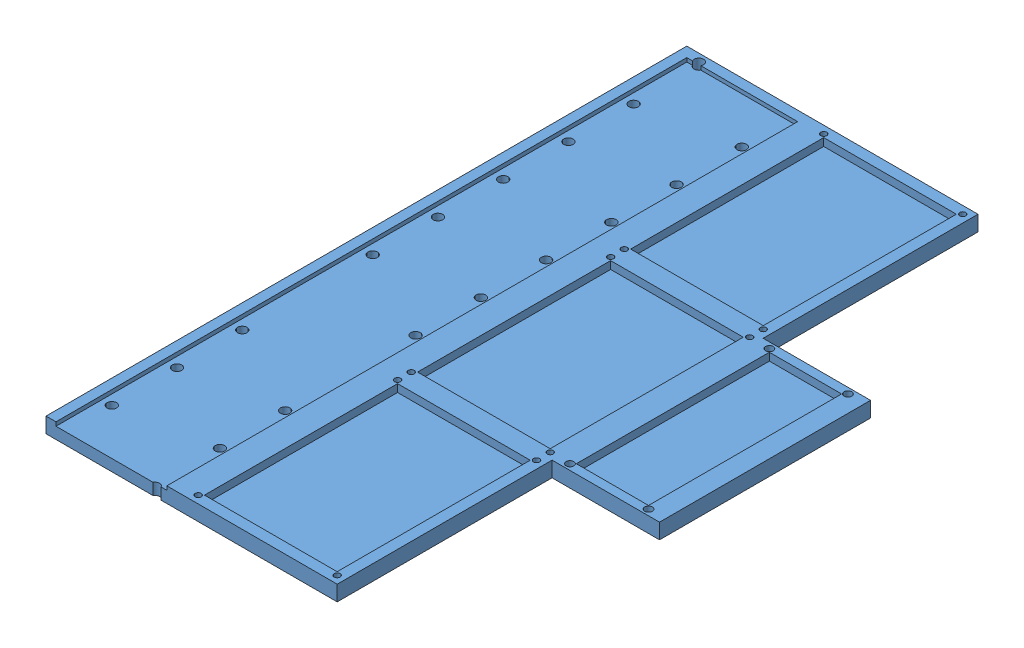
SolidWorks assembly Driver_power_housing_v1, configuration Default. Lengths in mm.
Overall size (131.94 5.08 212.09).
15 component instances, 4 part files, 17 mates.
Components (placement in the parent):
- pcb3x7-1: pcb3x7 [Default] at (-73.0022 6.604 -102.1286) x (0 0 -1) z (-1 0 0) size (70 1.52 30) (hidden)
- Carte proto 7x5.stp-1: Carte proto 7x5.stp [Default] at (-114.2326 6.58 -178.1987) x (0 0 1) z (0 -1 0) size (70 50 1.55) (hidden)
- DC-DC XL6009E1-2: DC-DC XL6009E1 [По умолчанию] at (-163.4226 5.08 -203.1712) size (43.3 13.75 21.1) (hidden)
- DC-DC XL6009E1-3: DC-DC XL6009E1 [По умолчанию] at (-163.4226 5.08 -181.5812) size (43.3 13.75 21.1) (hidden)
- DC-DC XL6009E1-4: DC-DC XL6009E1 [По умолчанию] at (-163.4226 5.08 -159.9912) size (43.3 13.75 21.1) (hidden)
- DC-DC XL6009E1-5: DC-DC XL6009E1 [По умолчанию] at (-163.4226 5.08 -138.4012) size (43.3 13.75 21.1) (hidden)
- DC-DC XL6009E1-6: DC-DC XL6009E1 [По умолчанию] at (-163.4226 5.08 -116.8112) size (43.3 13.75 21.1) (hidden)
- DC-DC XL6009E1-7: DC-DC XL6009E1 [По умолчанию] at (-163.4226 5.08 -95.2212) size (43.3 13.75 21.1) (hidden)
- DC-DC XL6009E1-8: DC-DC XL6009E1 [По умолчанию] at (-163.4226 5.08 -73.6312) size (43.3 13.75 21.1) (hidden)
- DC-DC XL6009E1-9: DC-DC XL6009E1 [По умолчанию] at (-163.4226 5.08 -52.0412) size (43.3 13.75 21.1) (hidden)
- DC-DC XL6009E1-10: DC-DC XL6009E1 [По умолчанию] at (-163.4226 5.08 -30.4512) size (43.3 13.75 21.1) (hidden)
- DC-DC XL6009E1-11: DC-DC XL6009E1 [По умолчанию] at (-163.4226 5.08 -8.8612) size (43.3 13.75 21.1) (hidden)
- Part4^Driver_power_housing_v1-1: Part4^Driver_power_housing_v1 [Default] at origin size (131.94 5.08 212.09) (virtual)
- Carte proto 7x5.stp-2: Carte proto 7x5.stp [Default] at (-114.2326 6.58 -37.1537) x (0 0 -1) z (0 -1 0) size (70 50 1.55) (hidden)
- Carte proto 7x5.stp-3: Carte proto 7x5.stp [Default] at (-114.2326 6.58 -107.6762) x (0 0 -1) z (0 -1 0) size (70 50 1.55) (hidden)
Mates (geometry in assembly coordinates):
- Coincident11: coincident: plane of DC-DC XL6009E1-2 through (-185.0726 6.68 -192.6212) normal (-1 0 0); plane of Part4^Driver_power_housing_v1-1 through (-185.0726 5.08 -1.6312) normal (-1 0 0)
- Coincident12: coincident: plane of DC-DC XL6009E1-2 through (-163.4226 5.08 -203.1712) normal (0 -1 0); plane of Part4^Driver_power_housing_v1-1 through (0 5.08 0) normal (0 1 0)
- Coincident30: coincident: plane of DC-DC XL6009E1-2 through (-185.0726 6.68 -213.7212) normal (0 0 -1); plane of Part4^Driver_power_housing_v1-1 through (-88.6883 5.08 -213.7212) normal (0 0 -1)
- Coincident14: coincident: plane of pcb3x7-1 through (-73.0022 5.08 -102.1286) normal (0 -1 0); plane of Part4^Driver_power_housing_v1-1 through (0 5.08 0) normal (0 1 0)
- Parallel2: parallel: plane of pcb3x7-1 through (-86.6926 5.08 -72.6762) normal (-1 0 0); plane of DC-DC XL6009E1-2 through (-141.7726 6.68 -192.6212) normal (1 0 0)
- Distance3: distance = 2.54 mm: plane of pcb3x7-1 through (-86.6926 5.08 -72.6762) normal (-1 0 0); plane of Carte proto 7x5.stp-3 through (-89.2326 6.58 -72.6762) normal (1 0 0)
- Coincident17: coincident: plane of Carte proto 7x5.stp-1 through (-114.2326 5.08 -178.1987) normal (0 -1 0); plane of Part4^Driver_power_housing_v1-1 through (0 5.08 0) normal (0 1 0)
- Width1: width: plane of pcb3x7-1 through (-56.6926 5.08 -142.6762) normal (0 0 -1); plane of pcb3x7-1 through (-56.6926 5.08 -72.6762) normal (0 0 1); plane of Part4^Driver_power_housing_v1-1 through (-88.6883 5.08 -1.6312) normal (0 0 1); plane of Part4^Driver_power_housing_v1-1 through (-88.6883 5.08 -213.7212) normal (0 0 -1)
- Coincident201: coincident: plane of Part4^Driver_power_housing_v1-1 through (0 5.08 0) normal (0 1 0); line of Carte proto 7x5.stp-2 through (-89.2326 5.08 -72.1537) axis (0 0 1)
- Width4: width: plane of Carte proto 7x5.stp-3 through (-89.2326 6.58 -142.6762) normal (0 0 -1); plane of Carte proto 7x5.stp-3 through (-139.2326 6.58 -72.6762) normal (0 0 1); plane of Part4^Driver_power_housing_v1-1 through (-88.6883 5.08 -1.6312) normal (0 0 1); plane of Part4^Driver_power_housing_v1-1 through (-88.6883 5.08 -213.7212) normal (0 0 -1)
- Coincident24: coincident: plane of Part4^Driver_power_housing_v1-1 through (0 5.08 0) normal (0 1 0); plane of Carte proto 7x5.stp-3 through (-114.2326 5.08 -107.6762) normal (0 -1 0)
- Distance6: distance = 2.54 mm: plane of Carte proto 7x5.stp-3 through (-139.2326 6.58 -142.6762) normal (-1 0 0); plane of DC-DC XL6009E1-2 through (-141.7726 6.68 -192.6212) normal (1 0 0)
- Coincident29: coincident: plane of Carte proto 7x5.stp-1 through (-139.2326 6.58 -213.1987) normal (-1 0 0); plane of Carte proto 7x5.stp-3 through (-139.2326 6.58 -142.6762) normal (-1 0 0)
- Width6: width: plane of Carte proto 7x5.stp-1 through (-139.2326 6.58 -143.1987) normal (0 0 1); plane of Carte proto 7x5.stp-1 through (-89.2326 6.58 -213.1987) normal (0 0 -1); plane of Part4^Driver_power_housing_v1-1 through (-88.6883 5.08 -213.7212) normal (0 0 -1); plane of Carte proto 7x5.stp-3 through (-89.2326 6.58 -142.6762) normal (0 0 -1)
- Width7: width: plane of Carte proto 7x5.stp-2 through (-89.2326 6.58 -72.1537) normal (0 0 -1); plane of Carte proto 7x5.stp-2 through (-139.2326 6.58 -2.1537) normal (0 0 1); plane of Part4^Driver_power_housing_v1-1 through (-88.6883 5.08 -1.6312) normal (0 0 1); plane of Carte proto 7x5.stp-3 through (-139.2326 6.58 -72.6762) normal (0 0 1)
- Coincident32: coincident: plane of Part4^Driver_power_housing_v1-1 through (0 5.08 0) normal (0 1 0); plane of Carte proto 7x5.stp-2 through (-114.2326 5.08 -37.1537) normal (0 -1 0)
- Coincident33: coincident: plane of Carte proto 7x5.stp-2 through (-139.2326 6.58 -72.1537) normal (-1 0 0); plane of Carte proto 7x5.stp-3 through (-139.2326 6.58 -142.6762) normal (-1 0 0)
